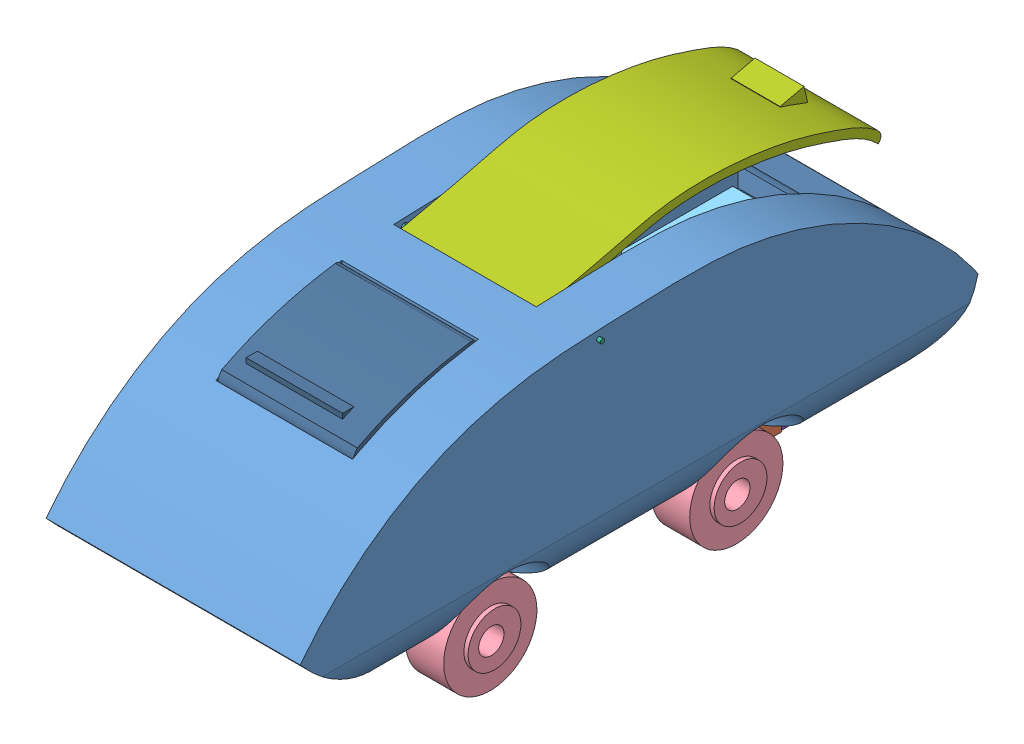
SolidWorks assembly Assem4final, configuration Default. Lengths in mm.
Overall size (68.72 90.43 160).
16 component instances, 10 part files, 25 mates.
Components (placement in the parent):
- great2-1: great2 [Default] at (12.501 85.1496 207.7394) size (68.72 59.93 160)
- chas-2: chas [Default] at (57.1786 63.6501 166.7485) x (0 0 -1) z (1 0 0) size (99.01 28.44 31.38)
- rode-1: rode [Default] at (18.4567 64.1501 159.2485) x (1 0 0) z (0 0.838192 -0.545376) size (46 5.6 5.6)
- tyre-1: tyre [Default] at (15.8475 64.1368 158.4941) x (1 0 0) z (0 0.017653 0.999844) size (10 22 22)
- tyre-2: tyre [Default] at (58.1744 64.0857 99.4641) x (1 0 0) z (0 0.001035 0.999999) size (10 22 22)
- tyre-3: tyre [Default] at (59.1317 64.097 158.4958) x (1 0 0) z (0 0.070456 0.997515) size (10 22 22)
- tyre-5: tyre [Default] at (27.5944 64.0685 100.973) x (-1 0 0) z (0 0.023804 -0.999717) size (10 22 22)
- inner cover-3: inner cover [Default] at (26.6629 85.1496 139.8164) size (33.66 8 80)
- rod 2-1: rod 2 [Default] at (23.401 116.5441 137.271) x (1 0 0) z (0 -0.784835 0.619704) size (50 1 1)
- door 1-2: door 1 [Default] at (27.3229 70.1567 -82.1147) x (1 0 0) z (0 -0.223119 0.974791) size (33 23.75 80.06)
- prop support-3: prop support [Default] at (56.886 60.7046 78.7485) x (0 0 -1) z (1 0 0) size (8 4 30)
- prop-5: prop [Default] at (49.386 62.7046 70.7485) size (8.54 8.34 8)
- prop-6: prop [Default] at (41.886 62.7046 70.7485) size (8.54 8.34 8)
- prop-7: prop [Default] at (34.3775 62.7046 70.7485) size (8.54 8.34 8)
- rod 2-2: rod 2 [Default] at (12.5123 116.433 153.6525) x (1 0 0) z (0 -0.459735 0.888056) size (50 1 1)
- small door-2: small door [Default] at (26.8195 45.9744 0.038) x (1 0 0) z (0 0.003896 0.999992) size (32.01 11.12 29.03)
Mates (geometry in assembly coordinates):
- Coincident4: coincident: plane of chas-2 through (57.1786 64.6501 166.7485) normal (0 1 0); plane of great2-1 through (132.501 64.6501 106.5034) normal (0 -1 0)
- Concentric1: concentric: cylinder of chas-2 through (70.1786 64.1501 159.2485) axis (-1 0 0) radius 3; cylinder of rode-1 through (64.4567 64.1501 159.2485) axis (-1 0 0) radius 2.8
- Concentric3: concentric: circle of rode-1; cylinder of tyre-1 through (33.8475 64.1501 159.2485) axis (-1 0 0) radius 3
- Concentric5: concentric: circle of rode-1; circle of tyre-3
- Coincident16: coincident: plane of great2-1 through (12.501 85.1496 207.7394) normal (0 1 0); plane of inner cover-3 through (26.6629 85.1496 139.8164) normal (0 -1 0)
- Coincident17: coincident: plane of great2-1 through (60.3229 137.1496 58.5329) normal (-1 0 0); plane of inner cover-3 through (60.3229 86.1496 139.8164) normal (1 0 0)
- Parallel6: parallel: plane of great2-1 through (26.6667 137.1496 58.5329) normal (1 0 0); plane of inner cover-3 through (26.6629 86.1496 139.8164) normal (-1 0 0)
- Coincident19: coincident: plane of great2-1 through (26.6667 137.1496 139.8164) normal (0 0 -1); line of inner cover-3 through (26.6629 86.1496 139.8164) axis (1 0 0)
- Concentric9: concentric: circle of great2-1; circle of rod 2-1
- Concentric11: concentric: cylinder of rod 2-1 through (73.401 116.5441 137.271) axis (-1 0 0) radius 0.5; cylinder of door 1-2 through (87.3229 116.5441 137.271) axis (-1 0 0) radius 0.55
- Coincident22: coincident: plane of great2-1 through (60.3229 137.1496 58.5329) normal (-1 0 0); plane of door 1-2 through (60.3229 124.4826 99.3116) normal (1 0 0)
- Parallel7: parallel: plane of great2-1 through (26.6667 137.1496 58.5329) normal (1 0 0); plane of door 1-2 through (27.3229 124.4826 99.3116) normal (-1 0 0)
- Coincident28: coincident: plane of chas-2 through (31.1791 63.6501 80.7485) normal (1 0 0); plane of prop support-3 through (31.1791 63.6084 77.7485) normal (-1 0 0)
- Parallel13: parallel: plane of chas-2 through (53.1786 63.6501 77.7485) normal (-1 0 0); plane of prop support-3 through (52.6854 63.8508 79.7485) normal (1 0 0)
- Coincident30: coincident: plane of chas-2 through (57.1786 64.6501 78.7485) normal (0 0 -1); plane of prop support-3 through (56.886 60.7046 78.7485) normal (0 0 1)
- Coincident31: coincident: plane of prop support-3 through (49.386 62.7046 74.7485) normal (0 0 -1); plane of prop-5 through (49.386 62.7046 74.7485) normal (0 0 1)
- Concentric12: concentric: cylinder of prop support-3 through (49.386 62.7046 74.7485) axis (0 0 -1) radius 0.5192; cylinder of prop-5 through (49.386 62.7046 74.7485) axis (0 0 -1) radius 0.5047
- Coincident32: coincident: plane of prop support-3 through (41.886 62.7046 74.7485) normal (0 0 -1); plane of prop-6 through (41.886 62.7046 74.7485) normal (0 0 1)
- Concentric13: concentric: cylinder of prop support-3 through (41.886 62.7046 74.7485) axis (0 0 -1) radius 0.5838; cylinder of prop-6 through (41.886 62.7046 74.7485) axis (0 0 -1) radius 0.5047
- Coincident33: coincident: plane of prop support-3 through (34.3775 62.7046 74.7485) normal (0 0 -1); plane of prop-7 through (34.3775 62.7046 74.7485) normal (0 0 1)
- Concentric14: concentric: cylinder of prop support-3 through (34.3775 62.7046 74.7485) axis (0 0 -1) radius 0.5816; cylinder of prop-7 through (34.3775 62.7046 74.7485) axis (0 0 -1) radius 0.5047
- Concentric16: concentric: cylinder of great2-1 through (11.501 116.433 153.6525) axis (1 0 0) radius 0.5578; cylinder of rod 2-2 through (62.5123 116.433 153.6525) axis (-1 0 0) radius 0.5
- Concentric19: concentric: cylinder of rod 2-2 through (62.5123 116.433 153.6525) axis (-1 0 0) radius 0.5; cylinder of small door-2 through (60.8195 116.433 153.6525) axis (-1 0 0) radius 0.5
- Coincident37: coincident: plane of great2-1 through (26.8195 161.1496 152.2297) normal (1 0 0); plane of small door-2 through (26.8195 112.3483 167.4133) normal (-1 0 0)
- Parallel16: parallel: plane of great2-1 through (59.0518 161.1496 152.2297) normal (-1 0 0); plane of small door-2 through (58.8195 112.3483 167.4133) normal (1 0 0)
